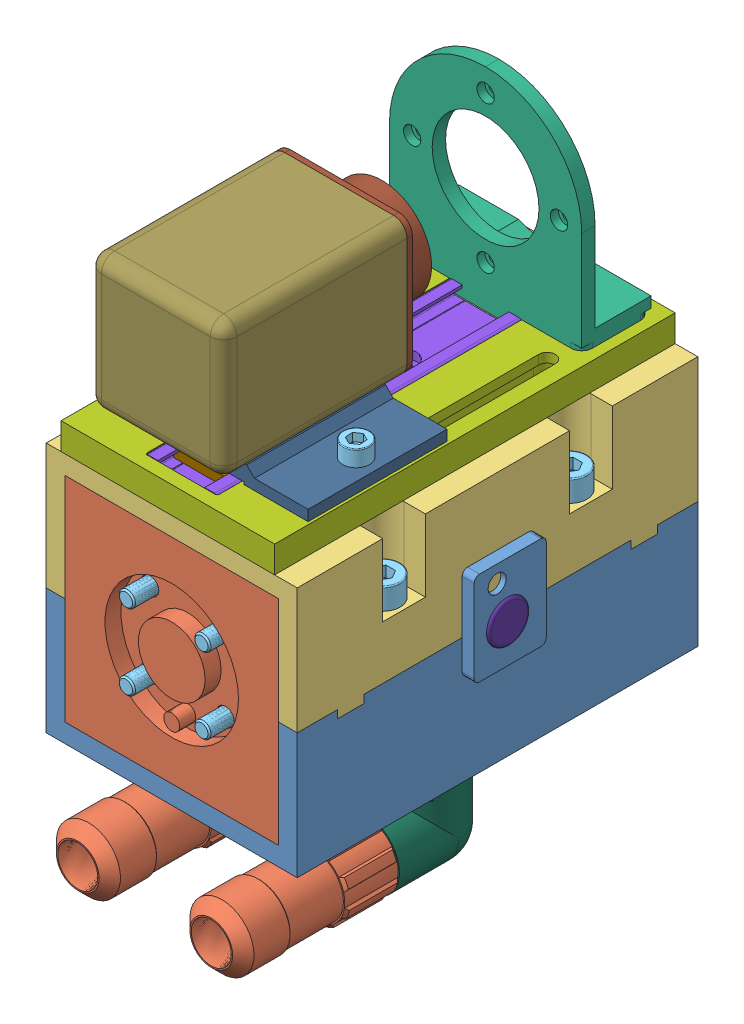
SolidWorks assembly Montagem_2, configuration Default. Lengths in mm.
Overall size (99.41 221.55 226.33).
39 component instances, 22 part files, 50 mates.
Components (placement in the parent):
- Estrutura_bottom-1: Estrutura_bottom [Default] at (58.6974 -11.7987 40.1528) size (94 47 150)
- Acoplamento_robot_50mm-1: Acoplamento_robot_50mm [Default] at (58.6974 28.2013 25.1528) size (86 86 89.49)
- Estrutura_top-1: Estrutura_top [Default] at (58.6974 75.2013 40.1528) x (-1 0 0) z (0 0 1) size (94 50 150)
- robot_fix-2: robot_fix [Default] at (58.6974 28.2013 -94.8472) size (86 86 102.04)
- Socket Head Cap Screw_ISO-2: Socket Head Cap Screw_ISO [ISO 4762 M8 x 40 --- 28C] at (19.6974 56.2013 -69.8472) x (0 -1 0) z (0 0 1) size (48 13 13)
- Socket Head Cap Screw_ISO-3: Socket Head Cap Screw_ISO [ISO 4762 M8 x 40 --- 28C] at (97.6974 56.2013 -69.8472) x (0 -1 0) z (0 0 1) size (48 13 13)
- Socket Head Cap Screw_ISO-4: Socket Head Cap Screw_ISO [ISO 4762 M8 x 40 --- 28C] at (97.6974 56.2013 0.1528) x (0 -1 0) z (0 0 1) size (48 13 13)
- Socket Head Cap Screw_ISO-5: Socket Head Cap Screw_ISO [ISO 4762 M8 x 40 --- 28C] at (19.6974 56.2013 0.1528) x (0 -1 0) z (0 0 1) size (48 13 13)
- Acoplamento_garra_50mm-2: Acoplamento_garra_50mm [Default] at (58.6974 28.2013 71.1528) size (60 60 102.04) (hidden)
- Socket Head Cap Screw_ISO-6: Socket Head Cap Screw_ISO [ISO 4762 M6 x 12 --- 12C] at (72.8395 42.3434 25.1528) x (0 0 1) z (-1 0 0) size (18 10 10)
- Socket Head Cap Screw_ISO-7: Socket Head Cap Screw_ISO [ISO 4762 M6 x 12 --- 12C] at (44.5553 42.3434 25.1528) x (0 0 1) z (-1 0 0) size (18 10 10)
- Socket Head Cap Screw_ISO-8: Socket Head Cap Screw_ISO [ISO 4762 M6 x 12 --- 12C] at (72.8395 14.0591 25.1528) x (0 0 1) z (-1 0 0) size (18 10 10)
- Socket Head Cap Screw_ISO-9: Socket Head Cap Screw_ISO [ISO 4762 M6 x 12 --- 12C] at (44.5553 14.0591 25.1528) x (0 0 1) z (-1 0 0) size (18 10 10)
- garra_teste-1: garra_teste [Default] at (58.6974 28.2013 -125.8472) size (80 80 89.49) (hidden)
- Socket Head Cap Screw_ISO-10: Socket Head Cap Screw_ISO [ISO 4762 M6 x 12 --- 12C] at (72.8395 14.0591 -125.8472) x (0 0 1) z (-1 0 0) size (18 10 10) (hidden)
- Socket Head Cap Screw_ISO-11: Socket Head Cap Screw_ISO [ISO 4762 M6 x 12 --- 12C] at (44.5553 14.0591 -125.8472) x (0 0 1) z (-1 0 0) size (18 10 10) (hidden)
- Socket Head Cap Screw_ISO-12: Socket Head Cap Screw_ISO [ISO 4762 M6 x 12 --- 12C] at (44.5553 42.3434 -125.8472) x (0 0 1) z (-1 0 0) size (18 10 10) (hidden)
- Socket Head Cap Screw_ISO-13: Socket Head Cap Screw_ISO [ISO 4762 M6 x 12 --- 12C] at (72.8395 42.3434 -125.8472) x (0 0 1) z (-1 0 0) size (18 10 10) (hidden)
- Conjunto_visao-1: Conjunto_visao [Default] at (57.2393 75.2013 -34.8472) x (-1 0 0) z (0 0 -1) size (80 85.3 179.1)
  - Apoio_iluminacaoLEDs-1: Apoio_iluminacaoLEDs [Default] at (0 49.3 49) size (72 79.3 83.14)
  - Apoio_sistema_visao-1: Apoio_sistema_visao [Default] at origin size (80 10 150)
  - Calha_deslizante_27mm-1: Calha_deslizante_27mm [Default] at (0 1.5 44) x (1 0 0) z (0 1 0) size (27 114 8.7)
  - Carro_deslizante_27mm-1: Carro_deslizante_27mm [Default] at (0 1.45 -41.4686) x (1 0 0) z (0 1 0) size (23.9 40 5.35)
  - Apoio_camara_27mm-1: Apoio_camara_27mm [Default] at (0 10 -61.4686) x (-1 0 0) z (0 0 -1) size (54 6.9 52)
  - Camara-1: Camara [Default] at (-9.935 38.5559 -27.3366) size (50.8 57.8 84.8)
    - Encaixe_lente-1: Encaixe_lente [Default] at (9.935 10.7441 16.5114) size (50.8 50.8 16.1)
    - Carapaca-1: Carapaca [Default] at (9.935 10.7441 -17.8386) size (50.8 57.8 68.7)
  - Hex Nut GradeC_ISO-1: Hex Nut GradeC_ISO [Hexagon Nut ISO - 4034 - M6 - C] at (-31 6.5 -35.4686) x (1 0 0) z (0 1 0) size (10 11.55 6.1)
  - Socket Head Cap Screw_ISO-2: Socket Head Cap Screw_ISO [ISO 4762 M6 x 12 --- 12C] at (-31 20 -35.4686) x (0 -1 0) z (-0.997267 0 0.073888) size (18 10 10)
- Caixa_servo-1: Caixa_servo [Default] at (38.2443 -27.7987 -77.8472) size (25 18 64)
- Conector_electrico-1: Conector_electrico [Default] at (33.6974 -16.7987 -29.8472) x (0 0 1) z (1 0 0) size (52.9 41.5 25.6)
- Conector_electrico-2: Conector_electrico [Default] at (83.6974 -16.7987 -29.8472) x (0 0 1) z (1 0 0) size (52.9 41.5 25.6)
- Conjunto_sensor-1: Conjunto_sensor [Default] at (95.2021 29.691 -33.63) x (0 -1 0) z (0 0 1) size (35 21.4 27)
  - Placa-1: Placa [Default] at (0.0753 1.0047 -1.4363) x (0 0 -1) z (-1 0 0) size (19.9 1.5 22.1)
  - Sensor-1: Sensor [Default] at (0.0753 1.9047 -0.3263) x (0 0 1) z (-1 0 0) size (15.5 18 15.5)
  - Base-1: Base [Default] at (-2.8747 -5.4953 -1.4863) size (35 9.5 27)
  - Tampa2-1: Tampa2 [Default] at (-2.8747 13.0047 -1.4863) x (1 0 0) z (0 0 -1) size (35 15.5 27)
- Conectror_electrico_plug-1: Conectror_electrico_plug [Default] at (83.6974 -45.7987 -7.6472) x (-0.998562 -0.053604 0) z (0 0 -1) size (25.13 25.13 70.62)
- Conectror_electrico_plug-2: Conectror_electrico_plug [Default] at (33.6974 -45.7987 -7.6472) x (-0.969923 0.243412 0) z (0 0 -1) size (25.13 25.13 70.62)
Mates (geometry in assembly coordinates):
- Coincident2: coincident aligned: line of Estrutura_bottom-1 through (18.6974 -11.7987 40.1528) axis (1 0 0); line of Acoplamento_robot_50mm-1 through (18.6974 -11.7987 40.1528) axis (1 0 0)
- Coincident3: coincident anti-aligned: line of Estrutura_bottom-1 through (98.6974 28.2013 40.1528) axis (0 -1 0); line of Acoplamento_robot_50mm-1 through (98.6974 -11.7987 40.1528) axis (0 1 0)
- Coincident4: coincident anti-aligned: line of Acoplamento_robot_50mm-1 through (98.6974 68.2013 40.1528) axis (-1 0 0); line of Estrutura_top-1 through (18.6974 68.2013 40.1528) axis (1 0 0)
- Coincident5: coincident anti-aligned: line of Acoplamento_robot_50mm-1 through (18.6974 68.2013 40.1528) axis (0 -1 0); line of Estrutura_top-1 through (18.6974 28.2013 40.1528) axis (0 1 0)
- Coincident10: coincident anti-aligned: line of Estrutura_bottom-1 through (98.6974 -11.7987 -109.8472) axis (-1 0 0); line of robot_fix-2 through (18.6974 -11.7987 -109.8472) axis (1 0 0)
- Coincident11: coincident aligned: line of Estrutura_bottom-1 through (18.6974 28.2013 -109.8472) axis (0 -1 0); line of robot_fix-2 through (18.6974 68.2013 -109.8472) axis (0 -1 0)
- Coincident12: coincident anti-aligned: plane of Estrutura_top-1 through (97.6974 48.2013 0.1528) normal (0 1 0); plane of Socket Head Cap Screw_ISO-4 through (104.1974 48.2013 0.1528) normal (0 -1 0)
- Coincident13: coincident anti-aligned: plane of Estrutura_top-1 through (97.6974 48.2013 -69.8472) normal (0 1 0); plane of Socket Head Cap Screw_ISO-3 through (104.1974 48.2013 -69.8472) normal (0 -1 0)
- Concentric4: concentric aligned: cylinder of Estrutura_top-1 through (97.6974 48.2013 0.1528) axis (0 1 0) radius 4; cylinder of Socket Head Cap Screw_ISO-4 through (97.6974 87.9513 0.1528) axis (0 1 0) radius 4
- Concentric5: concentric aligned: cylinder of Estrutura_top-1 through (97.6974 48.2013 -69.8472) axis (0 1 0) radius 4; cylinder of Socket Head Cap Screw_ISO-3 through (97.6974 87.9513 -69.8472) axis (0 1 0) radius 4
- Coincident14: coincident anti-aligned: plane of Estrutura_top-1 through (19.6974 48.2013 0.1528) normal (0 1 0); plane of Socket Head Cap Screw_ISO-5 through (26.1974 48.2013 0.1528) normal (0 -1 0)
- Coincident15: coincident anti-aligned: plane of Estrutura_top-1 through (19.6974 48.2013 -69.8472) normal (0 1 0); plane of Socket Head Cap Screw_ISO-2 through (26.1974 48.2013 -69.8472) normal (0 -1 0)
- Concentric6: concentric aligned: cylinder of Estrutura_top-1 through (19.6974 48.2013 -69.8472) axis (0 1 0) radius 4; cylinder of Socket Head Cap Screw_ISO-2 through (19.6974 87.9513 -69.8472) axis (0 1 0) radius 4
- Concentric7: concentric aligned: cylinder of Estrutura_top-1 through (19.6974 48.2013 0.1528) axis (0 1 0) radius 4; cylinder of Socket Head Cap Screw_ISO-5 through (19.6974 87.9513 0.1528) axis (0 1 0) radius 4
- Concentric8: concentric aligned: cylinder of Acoplamento_robot_50mm-1 through (58.6974 28.2013 34.1528) axis (0 0 1) radius 12.5; cylinder of Acoplamento_garra_50mm-2 through (58.6974 28.2013 34.1528) axis (0 0 1) radius 12.5
- Concentric10: concentric anti-aligned: cylinder of Acoplamento_robot_50mm-1 through (58.6974 8.2013 34.1528) axis (0 0 1) radius 3; cylinder of Acoplamento_garra_50mm-2 through (58.6974 8.2013 34.1528) axis (0 0 -1) radius 3
- Coincident18: coincident anti-aligned: plane of Acoplamento_robot_50mm-1 through (58.6974 28.2013 34.1528) normal (0 0 1); plane of Acoplamento_garra_50mm-2 through (58.6974 28.2013 34.1528) normal (0 0 -1)
- Coincident19: coincident anti-aligned: plane of Acoplamento_robot_50mm-1 through (76.1395 42.3434 31.1528) normal (0 0 -1); plane of Socket Head Cap Screw_ISO-6 through (72.8395 47.3434 31.1528) normal (0 0 1)
- Coincident20: coincident anti-aligned: plane of Acoplamento_robot_50mm-1 through (47.8553 42.3434 31.1528) normal (0 0 -1); plane of Socket Head Cap Screw_ISO-7 through (44.5553 47.3434 31.1528) normal (0 0 1)
- Concentric11: concentric aligned: cylinder of Acoplamento_garra_50mm-2 through (72.8395 42.3434 34.1528) axis (0 0 -1) radius 2.5; cylinder of Socket Head Cap Screw_ISO-6 through (72.8395 42.3434 -6.5972) axis (0 0 -1) radius 3
- Concentric12: concentric aligned: cylinder of Acoplamento_garra_50mm-2 through (44.5553 42.3434 34.1528) axis (0 0 -1) radius 2.5; cylinder of Socket Head Cap Screw_ISO-7 through (44.5553 42.3434 -6.5972) axis (0 0 -1) radius 3
- Coincident21: coincident anti-aligned: plane of Acoplamento_robot_50mm-1 through (76.1395 14.0591 31.1528) normal (0 0 -1); plane of Socket Head Cap Screw_ISO-8 through (72.8395 19.0591 31.1528) normal (0 0 1)
- Coincident22: coincident anti-aligned: plane of Acoplamento_robot_50mm-1 through (47.8553 14.0591 31.1528) normal (0 0 -1); plane of Socket Head Cap Screw_ISO-9 through (44.5553 19.0591 31.1528) normal (0 0 1)
- Concentric13: concentric aligned: cylinder of Acoplamento_garra_50mm-2 through (72.8395 14.0591 34.1528) axis (0 0 -1) radius 2.5; cylinder of Socket Head Cap Screw_ISO-8 through (72.8395 14.0591 -6.5972) axis (0 0 -1) radius 3
- Concentric14: concentric aligned: cylinder of Acoplamento_garra_50mm-2 through (44.5553 14.0591 34.1528) axis (0 0 -1) radius 2.5; cylinder of Socket Head Cap Screw_ISO-9 through (44.5553 14.0591 -6.5972) axis (0 0 -1) radius 3
- Concentric17: concentric anti-aligned: cylinder of robot_fix-2 through (58.6974 8.2013 -116.8472) axis (0 0 -1) radius 3; cylinder of garra_teste-1 through (58.6974 8.2013 -116.8472) axis (0 0 1) radius 3
- Concentric18: concentric aligned: cylinder of robot_fix-2 through (58.6974 28.2013 -116.8472) axis (0 0 1) radius 12.5; cylinder of garra_teste-1 through (58.6974 28.2013 -116.8472) axis (0 0 1) radius 12.5
- Coincident24: coincident anti-aligned: plane of robot_fix-2 through (58.6974 28.2013 -116.8472) normal (0 0 -1); plane of garra_teste-1 through (58.6974 28.2013 -116.8472) normal (0 0 1)
- Coincident25: coincident anti-aligned: plane of garra_teste-1 through (76.1395 42.3434 -119.8472) normal (0 0 -1); plane of Socket Head Cap Screw_ISO-10 through (72.8395 19.0591 -119.8472) normal (0 0 1)
- Coincident26: coincident anti-aligned: plane of garra_teste-1 through (47.8553 42.3434 -119.8472) normal (0 0 -1); plane of Socket Head Cap Screw_ISO-11 through (44.5553 19.0591 -119.8472) normal (0 0 1)
- Coincident27: coincident anti-aligned: plane of Socket Head Cap Screw_ISO-13 through (72.8395 47.3434 -119.8472) normal (0 0 1); plane of garra_teste-1 through (76.1395 14.0591 -119.8472) normal (0 0 -1)
- Coincident28: coincident anti-aligned: plane of garra_teste-1 through (47.8553 14.0591 -119.8472) normal (0 0 -1); plane of Socket Head Cap Screw_ISO-12 through (44.5553 47.3434 -119.8472) normal (0 0 1)
- Concentric19: concentric aligned: cylinder of robot_fix-2 through (44.5553 14.0591 -116.8472) axis (0 0 -1) radius 2.5; cylinder of Socket Head Cap Screw_ISO-11 through (44.5553 14.0591 -157.5972) axis (0 0 -1) radius 3
- Concentric20: concentric aligned: cylinder of robot_fix-2 through (72.8395 14.0591 -116.8472) axis (0 0 -1) radius 2.5; cylinder of Socket Head Cap Screw_ISO-10 through (72.8395 14.0591 -157.5972) axis (0 0 -1) radius 3
- Concentric21: concentric aligned: cylinder of robot_fix-2 through (72.8395 42.3434 -116.8472) axis (0 0 -1) radius 2.5; cylinder of Socket Head Cap Screw_ISO-13 through (72.8395 42.3434 -157.5972) axis (0 0 -1) radius 3
- Concentric22: concentric aligned: cylinder of robot_fix-2 through (44.5553 42.3434 -116.8472) axis (0 0 -1) radius 2.5; cylinder of Socket Head Cap Screw_ISO-12 through (44.5553 42.3434 -157.5972) axis (0 0 -1) radius 3
- Coincident29: coincident anti-aligned: plane of Estrutura_top-1 through (105.6974 75.2013 -109.8472) normal (0 1 0); plane of Conjunto_visao-1/Apoio_sistema_visao-1 through (97.2393 75.2013 -109.8472) normal (0 -1 0)
- Coincident30: coincident aligned: line of Estrutura_top-1 through (105.6974 75.2013 -109.8472) axis (-1 0 0); line of Conjunto_visao-1/Apoio_sistema_visao-1 through (97.2393 75.2013 -109.8472) axis (-1 0 0)
- Coincident31: coincident anti-aligned: plane of Estrutura_bottom-1 through (11.6974 -18.7987 -109.8472) normal (0 -1 0); plane of Caixa_servo-1 through (13.2443 -18.7987 -55.8472) normal (0 1 0)
- Coincident32: coincident aligned: line of Estrutura_bottom-1 through (105.6974 -18.7987 -109.8472) axis (-1 0 0); line of Caixa_servo-1 through (38.2443 -18.7987 -109.8472) axis (-1 0 0)
- Concentric31: concentric aligned: cylinder of Estrutura_bottom-1 through (33.6974 28.2023 -29.8472) axis (0 -1 0) radius 10; cylinder of Conector_electrico-1 through (33.6974 -16.7987 -29.8472) axis (0 -1 0) radius 10
- Concentric32: concentric aligned: cylinder of Estrutura_bottom-1 through (83.6974 28.2023 -29.8472) axis (0 -1 0) radius 10; cylinder of Conector_electrico-2 through (83.6974 -16.7987 -29.8472) axis (0 -1 0) radius 10
- Coincident41: coincident: plane of Estrutura_bottom-1 through (18.6974 -16.7987 -44.8472) normal (0 -1 0); line of Conector_electrico-2 through (93.9974 -16.7987 -17.0472) axis (-1 0 0)
- Coincident42: coincident: plane of Estrutura_bottom-1 through (18.6974 -16.7987 -44.8472) normal (0 -1 0); line of Conector_electrico-1 through (43.9974 -16.7987 -17.0472) axis (-1 0 0)
- Coincident45: coincident anti-aligned: plane of Estrutura_bottom-1 through (98.6974 28.2013 -109.8472) normal (-1 0 0); plane of ? through (98.6974 -4.7453 -54.2054) normal (1 0 0)
- Parallel3: parallel anti-aligned: line of Estrutura_bottom-1 through (98.6974 -11.7987 -9.7971) axis (0 1 0); line of ? through (98.6974 59.2547 -54.2054) axis (0 -1 0)
- Coincident46: coincident anti-aligned: plane of Conector_electrico-2 through (83.6974 -45.7987 -7.6472) normal (0 0 1); plane of Conectror_electrico_plug-1 through (83.6974 -45.7987 -7.6472) normal (0 0 -1)
- Concentric33: concentric aligned: cylinder of Conector_electrico-2 through (83.6974 -45.7987 -7.6472) axis (0 0 -1) radius 10; cylinder of Conectror_electrico_plug-1 through (83.6974 -45.7987 10.3528) axis (0 0 -1) radius 11.5
- Concentric34: concentric aligned: cylinder of Conector_electrico-1 through (33.6974 -45.7987 -7.6472) axis (0 0 -1) radius 10; cylinder of Conectror_electrico_plug-2 through (33.6974 -45.7987 10.3528) axis (0 0 -1) radius 11.5
- Coincident48: coincident anti-aligned: plane of Conector_electrico-1 through (33.6974 -45.7987 -7.6472) normal (0 0 1); plane of Conectror_electrico_plug-2 through (33.6974 -45.7987 -7.6472) normal (0 0 -1)
